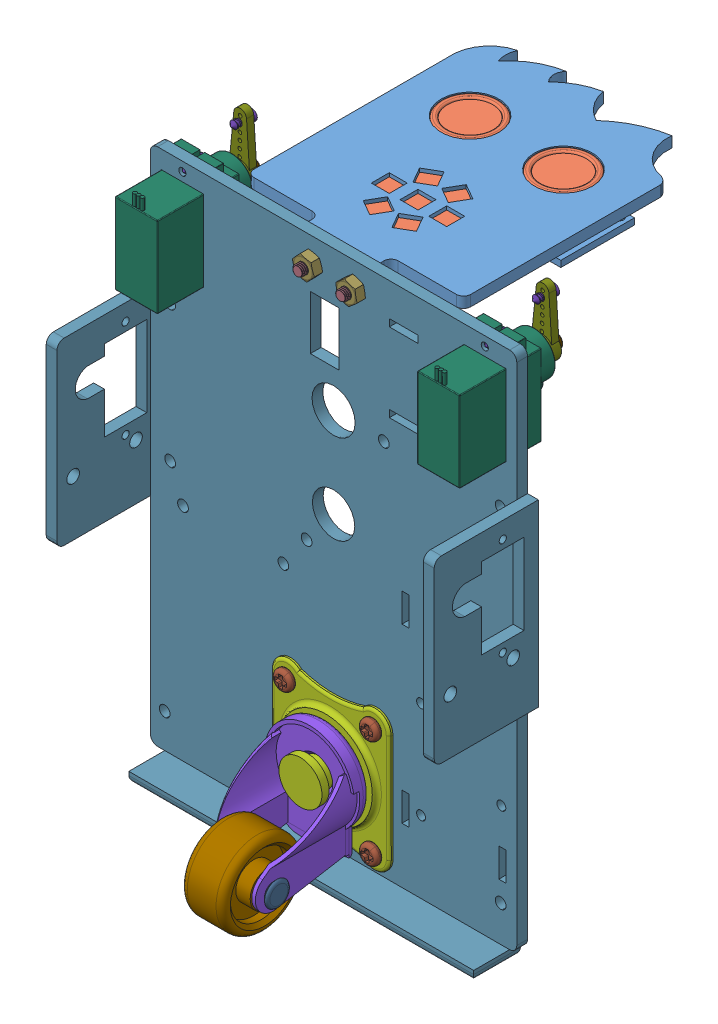
SolidWorks assembly DYOR_3D_LS_PU, configuration Predeterminado. Lengths in mm.
Overall size (108 155.56 112.97).
49 component instances, 20 part files, 15 mates.
Components (placement in the parent):
- HC-SR04 Ping Sensor-1: HC-SR04 Ping Sensor [Default] at (9.418 28.7888 -38.4611) x (0 0 -1) z (0 1 0) size (25.18 45 18.07)
  - PCB-1: PCB [Default] at origin size (20.5 45 1.75)
  - Transducer-1: Transducer [Default] at (0 -13 13.25) x (1 0 0) z (0 -1 0) size (15.88 12 15.88)
  - Transducer-2: Transducer [Default] at (0 13 13.25) x (1 0 0) z (0 -1 0) size (15.88 12 15.88)
  - 3 Pin Header 90 Degree-1: 3 Pin Header 90 Degree [Default] at (8.4275 0 -1.25) x (-1 0 0) z (0 -1 0) size (8 7.82 10)
  - 14 Pin SMT-1: 14 Pin SMT [Default] at (-0.35 -18.5 -0.85) x (0 -1 0) z (1 0 0) size (6 1.6 8.8)
  - 14 Pin SMT-2: 14 Pin SMT [Default] at (0 -0.3826 -0.85) x (1 0 0) z (0 1 0) size (6 1.6 8.8)
  - 14 Pin SMT-3: 14 Pin SMT [Default] at (0 17.5274 -0.85) x (1 0 0) z (0 1 0) size (6 1.6 8.8)
  - Cap1 SMT-1: Cap1 SMT [Default] at (-1.755 7.4774 -0.9689) x (0 1 0) z (-1 0 0) size (4.5 1.84 1.75)
  - Cap1 SMT-2: Cap1 SMT [Default] at (6.835 7.4774 -0.9689) x (0 1 0) z (-1 0 0) size (4.5 1.84 1.75)
  - Cap1 SMT-3: Cap1 SMT [Default] at (-6.835 7.4774 -0.9689) x (0 1 0) z (-1 0 0) size (4.5 1.84 1.75)
  - Cap1 SMT-4: Cap1 SMT [Default] at (4.295 7.4774 -0.9689) x (0 1 0) z (-1 0 0) size (4.5 1.84 1.75)
  - Cap1 SMT-5: Cap1 SMT [Default] at (1.755 7.4774 -0.9689) x (0 1 0) z (-1 0 0) size (4.5 1.84 1.75)
  - Cap1 SMT-6: Cap1 SMT [Default] at (-4.295 7.4774 -0.9689) x (0 1 0) z (-1 0 0) size (4.5 1.84 1.75)
  - HC-SR04 Crystal-1: HC-SR04 Crystal [Default] at (-8.3 0 1.75) x (0 -1 0) z (0 0 1) size (10 3.5 2.7)
- CA-1: CA [Predeterminado] at (-2.2402 -1.1323 0) x (1 0.000939 0) z (0 0 1) size (33 45.94 43.2)
  - Caster Wheel-1: Caster Wheel [Default] at (57.6387 -78.841 57.7572) x (0 1 0) z (-1 0 0) size (45.94 37.59 33)
    - caster holder-1: caster holder [Default] at (-24.0751 44.7184 29.5137) x (1 0 0) z (0 0 -1) size (39 9.27 33)
    - holder-1: holder [Default] at (-1.5751 42.9484 46.0137) x (0 0 1) z (1 0 0) size (25 28.07 31.31)
    - caster wheel-1: caster wheel [Default] at (-15.6961 19.9484 46.0137) x (0.997275 0.073773 0) z (0 0 1) size (23 23 14)
    - Part4-1: Part4 [Default] at (-15.6961 19.9484 55.0137) x (-0.978448 0.206495 0) z (0 0 -1) size (7 7 20)
  - M3x6 Philips Screw-1: M3x6 Philips Screw [Predeterminado] at (23.625 -65.4161 13.5389) size (5.3 5.3 7.81)
  - M3x6 Philips Screw-2: M3x6 Philips Screw [Predeterminado] at (-0.375 -65.4161 13.5389) size (5.3 5.3 7.81)
  - M3x6 Philips Screw-3: M3x6 Philips Screw [Predeterminado] at (-0.375 -95.4161 13.5389) size (5.3 5.3 7.81)
  - M3x6 Philips Screw-4: M3x6 Philips Screw [Predeterminado] at (23.625 -95.4161 13.5389) size (5.3 5.3 7.81)
  - M3 Nut-1: M3 Nut [Predeterminado] at (23.625 -65.4161 11.0389) size (6.27 6.27 2.71)
  - M3 Nut-2: M3 Nut [Predeterminado] at (-0.375 -65.4161 11.0389) size (6.27 6.27 2.71)
  - M3 Nut-3: M3 Nut [Predeterminado] at (-0.375 -95.4161 11.0389) size (6.27 6.27 2.71)
  - M3 Nut-4: M3 Nut [Predeterminado] at (23.625 -95.4161 11.0389) size (6.27 6.27 2.71)
- M3x10 Philips Screw-2: M3x10 Philips Screw [Predeterminado] at (3.418 36.0388 6.5389) x (0.88719 -0.461404 0) z (0 0 -1) size (5.3 5.3 11.8)
- M3x10 Philips Screw-3: M3x10 Philips Screw [Predeterminado] at (15.418 36.0388 6.5389) x (0.471193 -0.88203 0) z (0 0 -1) size (5.3 5.3 11.8)
- M3 Nut-1: M3 Nut [Predeterminado] at (3.418 36.0388 16.5389) x (0.222076 0.975029 0) z (0 0 1) size (6.27 6.27 2.71)
- M3 Nut-2: M3 Nut [Predeterminado] at (15.418 36.0388 11.0389) x (-0.334718 -0.942319 0) z (0 0 -1) size (6.27 6.27 2.71)
- BasePU-1: BasePU [Predeterminado] at (-51.2528 96.5598 9.5389) size (108 147.56 29)
- PU-1: PU [Predeterminado] at (-155.9776 204.2742 -130.283) size (95.94 37.23 33.31)
  - sg90-1: sg90 [Default] at (201.5956 -166.7354 155.7219) x (0 -1 0) z (1 0 0) size (31.9 29.9 11.8)
  - sg90-2: sg90 [Default] at (117.452 -166.7354 155.7219) x (0 -1 0) z (1 0 0) size (31.9 29.9 11.8)
  - SG90 plastic Horn-1: SG90 plastic Horn [Default] at (123.352 -172.6354 127.0219) x (0.017141 0.999853 0) z (-0.999853 0.017141 0) size (19.4 4 7.07)
  - SG90 plastic Horn-2: SG90 plastic Horn [Default] at (207.4956 -172.6354 127.0219) x (0.020276 0.999794 0) z (-0.999794 0.020276 0) size (19.4 4 7.07)
  - M2x6 SelfTap Screw-1: M2x6 SelfTap Screw [Predeterminado] at (207.4956 -164.3354 136.8219) x (-0.923728 -0.383049 0) z (0 0 -1) size (3.4 3.28 6)
  - M2x6 SelfTap Screw-2: M2x6 SelfTap Screw [Predeterminado] at (207.4956 -191.6354 136.3219) x (-0.923728 -0.383049 0) z (0 0 -1) size (3.4 3.28 6)
  - M2x6 SelfTap Screw-3: M2x6 SelfTap Screw [Predeterminado] at (123.352 -164.3354 136.8219) x (-0.993348 0.115149 0) z (0 0 -1) size (3.4 3.28 6)
  - M2x6 SelfTap Screw-4: M2x6 SelfTap Screw [Predeterminado] at (123.352 -191.6354 136.8219) x (-0.923728 -0.383049 0) z (0 0 -1) size (3.4 3.28 6)
  - (M2_3_mm)_90116A007_METRIC 316 SS PAN HEAD PHILLIPS MACHINE SCREW-1: (M2_3_mm)_90116A007_METRIC 316 SS PAN HEAD PHILLIPS MACHINE SCREW [90116A007] at (123.352 -172.6354 127.0219) x (-0.923728 -0.383049 0) z (0 0 -1) size (4 4 4.68)
  - (M2_3_mm)_90116A007_METRIC 316 SS PAN HEAD PHILLIPS MACHINE SCREW-2: (M2_3_mm)_90116A007_METRIC 316 SS PAN HEAD PHILLIPS MACHINE SCREW [90116A007] at (207.4956 -172.6354 127.0219) x (-0.923728 -0.383049 0) z (0 0 -1) size (4 4 4.68)
  - M2x6 SelfTap Screw-5: M2x6 SelfTap Screw [Predeterminado] at (123.352 -160.1354 123.5219) x (-0.923728 -0.383049 0) z (0 0 -1) size (3.4 3.28 6)
  - M2x6 SelfTap Screw-6: M2x6 SelfTap Screw [Predeterminado] at (207.4956 -160.1354 123.5219) x (-0.923728 -0.383049 0) z (0 0 -1) size (3.4 3.28 6)
- Front_LS-1: Front_LS [Predeterminado] at (-51.2809 39.5388 -46.4821) x (1 0 0) z (0 1 0) size (60.34 72.38 11)
- ws8212-7-1: ws8212-7 [Predeterminado] at (9.418 38.5388 -10.9611) x (0 0 -1) z (0 1 0) size (24 24 3.1)
Mates (geometry in assembly coordinates):
- Concéntrica15: concentric: circle of M3 Nut-2; circle of BasePU-1
- Coincidente15: coincident: plane of M3 Nut-1 through (3.418 36.0388 12.5389) normal (0 0 -1); plane of BasePU-1 through (58.418 40.5388 12.5389) normal (0 0 1)
- Coincidente16: coincident: plane of M3 Nut-2 through (15.418 36.0388 12.5389) normal (0 0 -1); plane of BasePU-1 through (58.418 40.5388 12.5389) normal (0 0 1)
- Coincidente17: coincident: plane of BasePU-1 through (57.418 37.5388 12.5389) normal (0 -1 0); plane of PU-1/sg90-1 through (57.418 37.5388 25.4389) normal (0 1 0)
- Coincidente18: coincident: plane of BasePU-1 through (58.418 40.5388 9.5389) normal (0 0 -1); plane of PU-1/sg90-1 through (57.418 10.3388 9.5389) normal (0 0 1)
- Concéntrica16: concentric: circle of BasePU-1; circle of PU-1/M2x6 SelfTap Screw-2
- Coincidente19: coincident: plane of BasePU-1 through (58.418 40.5388 9.5389) normal (0 0 -1); plane of Front_LS-1 through (-0.582 42.5388 9.5389) normal (0 0 1)
- Concéntrica18: concentric: circle of BasePU-1; circle of Front_LS-1
- Paralelo1: parallel: plane of BasePU-1 through (-7.6975 42.5388 12.5389) normal (0 1 0); plane of Front_LS-1 through (-2.582 42.5388 8.5389) normal (0 1 0)
- Concéntrica19: concentric: circle of HC-SR04 Ping Sensor-1/Transducer-1; circle of Front_LS-1
- Concéntrica20: concentric: circle of HC-SR04 Ping Sensor-1/Transducer-2; circle of Front_LS-1
- Coincidente21: coincident: plane of HC-SR04 Ping Sensor-1/Transducer-2 through (-3.582 42.5388 -46.4011) normal (0 1 0); plane of Front_LS-1 through (-2.582 42.5388 8.5389) normal (0 1 0)
- Coincidente22: coincident: plane of Front_LS-1 through (3.918 42.5388 -8.4611) normal (-1 0 0); plane of ws8212-7-1 through (3.918 41.5388 -13.4611) normal (1 0 0)
- Coincidente23: coincident: plane of Front_LS-1 through (3.918 42.5388 -13.4611) normal (0 0 1); plane of ws8212-7-1 through (-1.082 41.5388 -13.4611) normal (0 0 -1)
- Distancia1: distance = 1 mm: plane of ws8212-7-1 through (9.418 41.5388 -10.9611) normal (0 1 0); plane of Front_LS-1 through (-2.582 42.5388 8.5389) normal (0 1 0)
